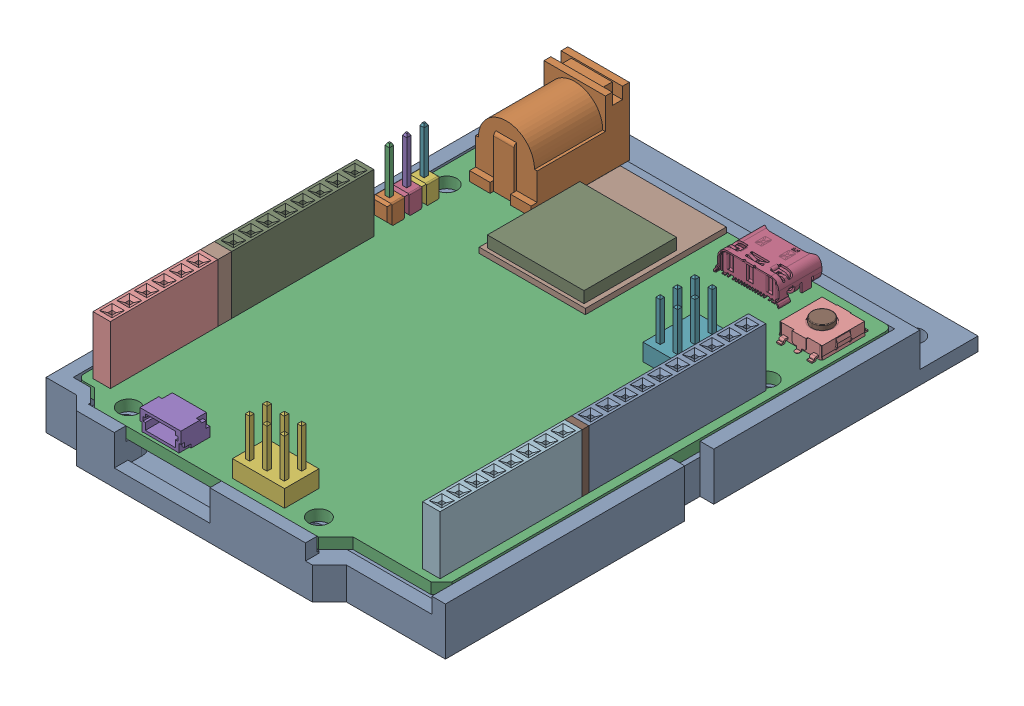
SolidWorks assembly Arduino_With_Mount_A, configuration Default. Lengths in mm.
Overall size (59.4 17.89 80.5).
2 component instances, 2 part files, 6 mates.
Components (placement in the parent):
- Arduino_Mount_B-2: Arduino_Mount_B [Default] at (0 2 0) x (-1 0 0) z (0 0 1) size (59.4 8 80.5)
- Arduino_Uno_R4_Wifi_A-1: Arduino_Uno_R4_Wifi_A [Default] at (-26.67 7 -30.29) x (0 0 1) z (0 1 0) size (70.54 53.34 14.5)
Mates (geometry in assembly coordinates):
- Coincident3: coincident anti-aligned: plane of Arduino_Mount_A-2 through (0 0 0) normal (0 -1 0)
- Coincident4: coincident aligned: plane of Arduino_Mount_A-2 through (0 2 0) normal (0 0 1)
- Coincident5: coincident anti-aligned: plane of Arduino_Mount_A-2 through (0 2 0) normal (-1 0 0)
- Width1: width aligned: plane of Arduino_Mount_A-2 through (0 2.5 38) normal (0 0 -1); plane of Arduino_Mount_A-2 through (0 2.5 -30) normal (0 0 1); plane of Arduino_Uno_R4_Wifi-1 through (-25.67 5.3937 -30.29) normal (0 0 -1); plane of Arduino_Uno_R4_Wifi-1 through (11.176 5.3937 38.29) normal (0 0 1)
- Width2: width anti-aligned: plane of Arduino_Uno_R4_Wifi-1 through (-26.67 5.3937 34.75) normal (-1 0 0); plane of Arduino_Uno_R4_Wifi-1 through (26.67 5.3937 -29.29) normal (1 0 0); plane of Arduino_Mount_A-2 through (-27 2.5 0) normal (1 0 0); plane of Arduino_Mount_A-2 through (27 2.5 0) normal (-1 0 0)
- Coincident8: coincident aligned: plane of Arduino_Mount_A-2 through (0 7 0) normal (0 1 0); plane of Arduino_Uno_R4_Wifi-1 through (-0.0974 7 3.3449) normal (0 1 0)
